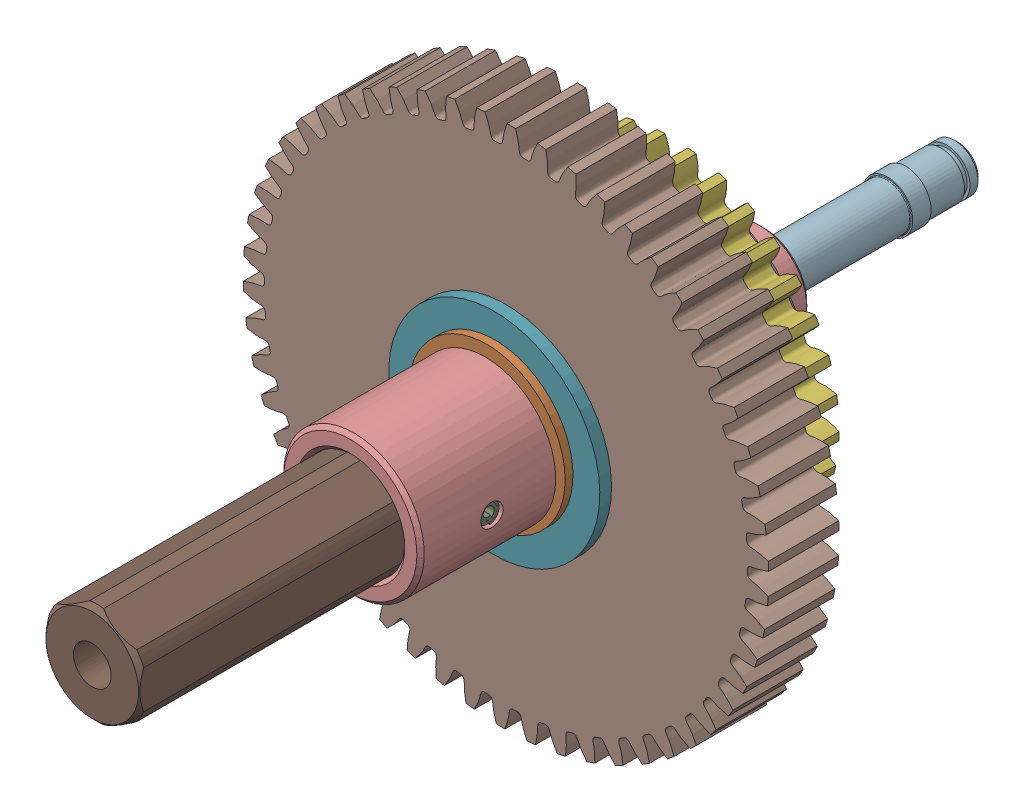
SolidWorks assembly 217-3291-001 Rev3, configuration Default. Lengths in mm.
Overall size (74.97 75.02 117.22).
19 component instances, 10 part files, 0 mates.
Components (placement in the parent):
- 217-2428-008 Rev2-1: 217-2428-008 Rev2 [Default] at (0 0 10.2679) size (31.75 31.75 1.59)
- 217-2428-028 Rev1_97633A250-1: 217-2428-028 Rev1_97633A250 [Default] at (0 0 37.1221) x (0 0 1) z (0.9357 -0.352797 0) size (1.07 23.39 21.18)
- 217-2428-007 Rev1-1: 217-2428-007 Rev1 [Default] at (4.5085 7.809 14.2494) x (0.57515 -0.320306 -0.752732) z (-0.697826 0.288078 -0.655782) size (6.35 6.35 6.35)
- 217-2428-007 Rev1-2: 217-2428-007 Rev1 [Default] at (3.1375 5.4343 26.9494) x (0.444163 0.822893 0.354354) z (0.803342 -0.540896 0.249144) size (6.35 6.35 6.35)
- 217-3212-101 Rev1-1: 217-3212-101 Rev1 [Default] at (-7.461 13.6656 45.3224) x (0.998507 0.054615 0) z (0 0 -1) size (46.46 46.56 12.7)
  - 217-2428-022 Rev1-1: 217-2428-022 Rev1 [Default] at (6.7035 14.0527 24.6087) size (28.57 28.57 6.1)
  - 217-3212-001 Rev1_34t-1: 217-3212-001 Rev1_34t [Default] at (6.7035 14.0527 27.9107) size (46.46 46.56 11.11)
- 217-3222-101 Rev1-1: 217-3222-101 Rev1 [Default] at (-16.5535 14.1005 52.7371) x (0.999887 0.015021 0) z (0 0 -1) size (73.87 73.92 12.7)
  - 217-2428-022 Rev1-1: 217-2428-022 Rev1 [Default] at (16.3398 14.3476 19.3234) size (28.57 28.57 6.1)
  - 217-3222-001 Rev1_Spur01-1: 217-3222-001 Rev1_Spur01 [Default] at (16.3398 14.3476 22.6254) x (0.999377 0.0353 0) z (0 0 1) size (71.39 71.45 11.11)
- 217-4098-000 Rev2-1: 217-4098-000 Rev2 [Default] x (0 1 0) z (0 0 1) size (22.23 22.23 117.22)
  - 217-4098-005 Rev1_91612A226-1: 217-4098-005 Rev1_91612A226 [Default] at (0 0 46.2661) x (-0.144757 0 0.989467) z (0 -1 0) size (3.02 3.15 18.22)
  - 217-4098-003 Rev2-1: 217-4098-003 Rev2 [Default] x (1 0 0) z (0 0 -1) size (22.23 22.23 55.94)
  - 217-4098-002 Rev3-1: 217-4098-002 Rev3 [Default] at (0 0 62.9285) x (0 0 1) z (-1 0 0) size (59.88 12.73 14.67)
  - 217-4098-004 Rev1-1: 217-4098-004 Rev1 [Default] at (0 0 14.2494) x (-0.610335 0.792144 0) z (0 0 1) size (11.68 11.68 56)
- 217-2428-007 Rev1-3: 217-2428-007 Rev1 [Default] at (4.355 -6.8759 14.2494) x (-0.564969 -0.337942 -0.752732) z (0.598396 0.460296 -0.655782) size (6.35 6.35 6.35)
- 217-2428-007 Rev1-4: 217-2428-007 Rev1 [Default] at (-8.2857 0.5994 14.2494) x (-0.010182 0.658248 -0.752732) z (0.09943 -0.748374 -0.655782) size (6.35 6.35 6.35)
- 217-2428-007 Rev1-5: 217-2428-007 Rev1 [Default] at (2.984 -4.5013 26.9494) x (0.490565 -0.796103 0.354354) z (-0.870101 -0.425267 0.249144) size (6.35 6.35 6.35)
- 217-2428-007 Rev1-6: 217-2428-007 Rev1 [Default] at (-5.5437 0.5994 26.9494) x (-0.934728 -0.02679 0.354354) z (0.066759 0.966163 0.249144) size (6.35 6.35 6.35)
